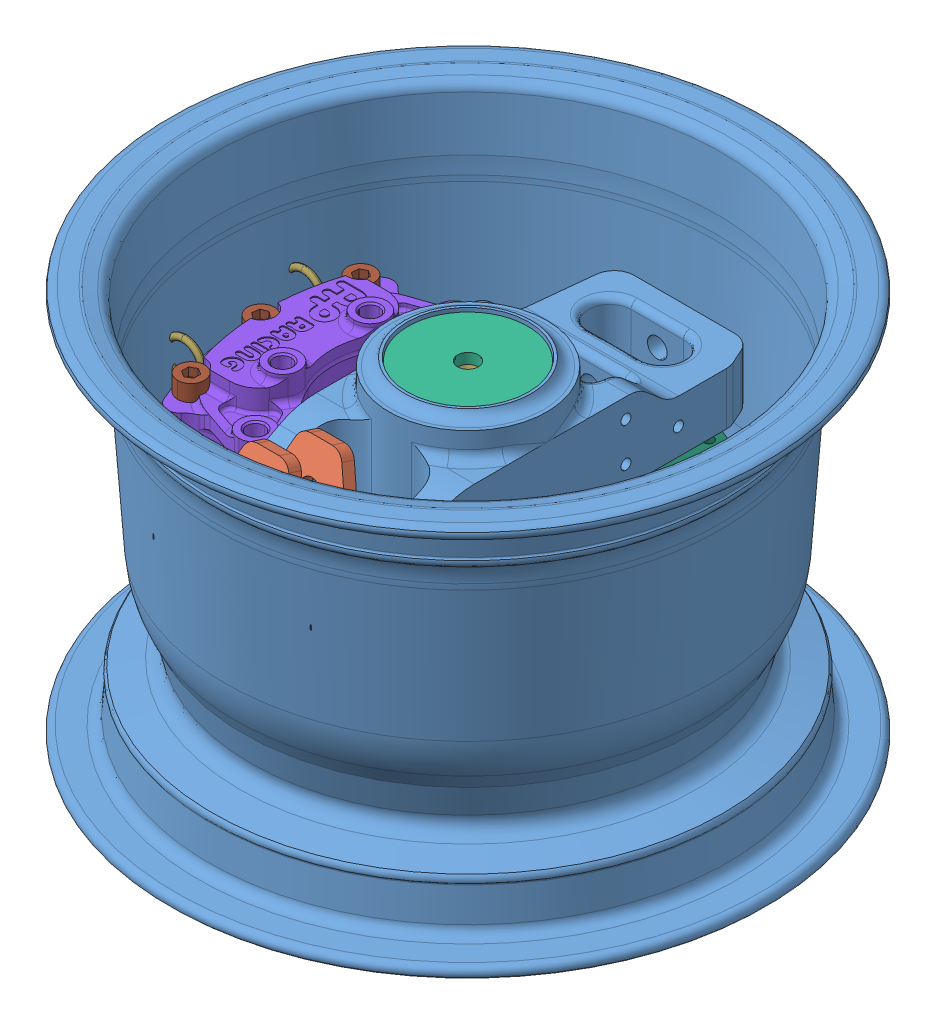
SolidWorks assembly WT-FRA0100-AH-Corner Assembly1, configuration Default. Lengths in mm.
Overall size (569.63 213.5 569.63).
47 component instances, 24 part files, 46 mates.
Components (placement in the parent):
- WT-FR####-AF-Upright1-1: WT-FR####-AF-Upright1 [Default] x (-1 0 0) z (0 0 -1) size (101.76 54.5 217.79)
- WT-FR####-AA-Camber Block1-1: WT-FR####-AA-Camber Block1 [Default] at (0 -9.355 94.5987) x (1 0 0) z (0 0.311078 0.950384) size (47.63 44.45 33.35)
- WT-FR10101-AB-Wheel Hub Front1-1: WT-FR10101-AB-Wheel Hub Front1 [Front] at (0 -47.0214 0) x (-0.796957 0 0.604036) z (0.604036 0 0.796957) size (96.32 138.68 96.32)
- FR1985-1932-TheTimkenCompany-3D-01-05-2023.stp1-1: FR1985-1932-TheTimkenCompany-3D-01-05-2023.stp1 [Default] at (0 -2.8702 0) x (0 -1 0) z (0.543016 0 0.839722) size (21.39 58.74 58.74)
- FR1985-1932-TheTimkenCompany-3D-01-05-2023.stp1-2: FR1985-1932-TheTimkenCompany-3D-01-05-2023.stp1 [Default] at (0 2.8702 0) x (0 1 0) z (-0.546944 0 0.837169) size (21.39 58.74 58.74)
- WT-FR####-AA-Front Grease Seal1-1: WT-FR####-AA-Front Grease Seal1 [Default] at (0 -24.9191 0) x (0.858041 0 -0.513581) z (0.513581 0 0.858041) size (58.42 7.71 58.42)
- WT-FR10106-AB-Backing Plate1-1: WT-FR10106-AB-Backing Plate1 [Default] at (0 21.8126 0) x (-0.663672 0 -0.748024) z (-0.748024 0 0.663672) size (57.91 5.08 57.91)
- WT-FR####-AB-Misuni Drive Pins1-1: WT-FR####-AB-Misuni Drive Pins1 [Default] at (31.8783 -46.4514 -24.1614) x (0 -1 0) z (0.99943 0 0.033765) size (21.1 11.95 11.95)
- WT-FR####-AB-Misuni Drive Pins1-2: WT-FR####-AB-Misuni Drive Pins1 [Default] at (-24.1614 -46.4514 -31.8783) x (0 -1 0) z (0.033765 0 -0.99943) size (21.1 11.95 11.95)
- WT-FR####-AB-Misuni Drive Pins1-3: WT-FR####-AB-Misuni Drive Pins1 [Default] at (-31.8783 -46.4514 24.1614) x (0 -1 0) z (-0.99943 0 -0.033765) size (21.1 11.95 11.95)
- WT-FR####-AB-Misuni Drive Pins1-4: WT-FR####-AB-Misuni Drive Pins1 [Default] at (24.1614 -46.4514 31.8783) x (0 -1 0) z (-0.033765 0 0.99943) size (21.1 11.95 11.95)
- FR-CP4227-2S01-1: FR-CP4227-2S01 [Default] at (15.8532 -32.3212 -0.8308) x (1 0 0) z (0 0 -1) size (71.54 66.42 130.94)
  - CP4227-2S0.STEP-1: CP4227-2S0.STEP [Default] x (0 0 -1) z (0 -1 0) size (130.94 71.54 66.42)
    - CP4227-101.STEP-1: CP4227-101.STEP [Default] at origin size (112 60.5 34.68)
    - CP4227-102.STEP-1: CP4227-102.STEP [Default] x (-1 0 0) z (0 0 -1) size (109 47.57 30.98)
    - cp3049-40a_CP4226-103.STEP-1: cp3049-40a_CP4226-103.STEP [Default] at (-23.4668 -94.12 -10.305) size (25.2 25.2 14.87)
    - cp3049-40a_CP4226-103.STEP-2: cp3049-40a_CP4226-103.STEP [Default] at (-23.4668 -94.12 10.305) x (-0.98369 0.179874 0) z (0 0 -1) size (25.2 25.2 14.87)
    - cp3049-40a_CP4226-103.STEP-3: cp3049-40a_CP4226-103.STEP [Default] at (23.4668 -94.12 10.305) x (-0.960147 0.279495 0) z (0 0 -1) size (25.2 25.2 14.87)
    - cp3049-40a_CP4226-103.STEP-4: cp3049-40a_CP4226-103.STEP [Default] at (23.4668 -94.12 -10.305) size (25.2 25.2 14.87)
    - cp3838-M08x1.25m_CP4477-110.STEP-1: cp3838-M08x1.25m_CP4477-110.STEP [Default] at (-41.1 -109.6 19.55) x (-0.998897 0.046962 0) z (0 0 -1) size (13 13 46)
    - cp3838-M08x1.25m_CP4477-110.STEP-2: cp3838-M08x1.25m_CP4477-110.STEP [Default] at (0 -116.83 19.55) x (-0.99038 0.138378 0) z (0 0 -1) size (13 13 46)
    - cp3838-M08x1.25m_CP4477-110.STEP-3: cp3838-M08x1.25m_CP4477-110.STEP [Default] at (41.1 -109.6 19.55) x (-1 -0.000032 0) z (0 0 -1) size (13 13 46)
    - cp4226-104_CP4226-104.STEP-1: cp4226-104_CP4226-104.STEP [Default] at (-29.0318 -116.44 -31.75) x (0 0 1) z (1 0 0) size (61.35 20.1 3)
    - cp4226-104_CP4226-104.STEP-2: cp4226-104_CP4226-104.STEP [Default] at (29.0318 -116.44 -31.75) x (0 0 1) z (1 0 0) size (61.35 20.1 3)
    - CP4469-101.STEP-1: CP4469-101.STEP [Default] at (-65.47 -82.62 -23.98) x (0 0.474307 -0.88036) z (1 0 0) size (9.24 8.21 29.15)
    - CP4469-101.STEP-2: CP4469-101.STEP [Default] at (65.47 -82.62 -23.98) x (0 0.509894 0.860237) z (-1 0 0) size (9.24 8.21 29.15)
    - CP4226-4m.STEP-1: CP4226-4m.STEP [Default] at (10.0433 -40.2815 10.305) x (0.970296 0.241922 0) z (0 0 -1) size (39.7 43.64 7)
    - CP4226-4m.STEP-2: CP4226-4m.STEP [Default] at (10.0433 -40.2815 -10.305) x (-0.970296 -0.241922 0) z (0 0 1) size (39.7 43.64 7)
    - CP4226-4m.STEP-3: CP4226-4m.STEP [Default] at (-10.0433 -40.2815 -10.305) x (-0.970296 0.241922 0) z (0 0 1) size (39.7 43.64 7)
    - CP4226-4m.STEP-4: CP4226-4m.STEP [Default] at (-10.0433 -40.2815 10.305) x (0.970296 -0.241922 0) z (0 0 -1) size (39.7 43.64 7)
- BR-FR20601-AA-Brake Rotor1-1: BR-FR20601-AA-Brake Rotor1 [Default] at (0 -32.3212 0) x (-0.921589 0 -0.388168) z (0.388168 0 -0.921589) size (190.5 4.76 190.5)
- BR-FR20602-AC-Brake Hat1-2: BR-FR20602-AC-Brake Hat1 [Default] at (0 -32.3212 0) x (-0.796957 0 0.604036) z (-0.604036 0 -0.796957) size (120.29 4.76 113.7)
- BR-FR20603-AA-Floating Bobbins1-1: BR-FR20603-AA-Floating Bobbins1 [Default] at (-7.5184 -32.4958 -59.8547) x (0.90465 0 -0.426156) z (-0.426156 0 -0.90465) size (12.7 8.29 12.7)
- BR-FR20603-AA-Floating Bobbins1-2: BR-FR20603-AA-Floating Bobbins1 [Default] at (48.0765 -32.4958 -36.4384) x (0.821387 0 0.570372) z (0.570372 0 -0.821387) size (12.7 8.29 12.7)
- BR-FR20603-AA-Floating Bobbins1-3: BR-FR20603-AA-Floating Bobbins1 [Default] at (55.5948 -32.4958 23.4162) x (-0.083263 0 0.996528) z (0.996528 0 0.083263) size (12.7 8.29 12.7)
- BR-FR20603-AA-Floating Bobbins1-4: BR-FR20603-AA-Floating Bobbins1 [Default] at (7.5184 -32.4958 59.8547) x (-0.90465 0 0.426156) z (0.426156 0 0.90465) size (12.7 8.29 12.7)
- BR-FR20603-AA-Floating Bobbins1-5: BR-FR20603-AA-Floating Bobbins1 [Default] at (-48.0765 -32.4958 36.4384) x (-0.821387 0 -0.570372) z (-0.570372 0 0.821387) size (12.7 8.29 12.7)
- BR-FR20603-AA-Floating Bobbins1-6: BR-FR20603-AA-Floating Bobbins1 [Default] at (-55.5948 -32.4958 -23.4162) x (0.083263 0 -0.996528) z (-0.996528 0 -0.083263) size (12.7 8.29 12.7)
- WT-FR20104-AC-Sensor Ring1-1: WT-FR20104-AC-Sensor Ring1 [Default] at (0 -28.3524 0) x (-0.796957 0 0.604036) z (0 -1 0) size (113.66 114.3 1.59)
- WT-FR00201-AA-OZ Centerlock 10in Wheel1-1: WT-FR00201-AA-OZ Centerlock 10in Wheel1 [Default] at (0 -58.4514 0) x (-0.388168 0 0.921589) z (0 -1 0) size (288.79 288.79 189.86)
- WT-FR10102-AA-Centerlock Nut1-1: WT-FR10102-AA-Centerlock Nut1 [Default] at (0 -109.0714 0) x (-0.796957 0 0.604036) z (0.604036 0 0.796957) size (66 31.75 66)
- WT_FRA####-AA-Toe Bracket1-1: WT_FRA####-AA-Toe Bracket1 [Default] at (15.6652 35.2295 -63.5947) x (1 0 0) z (0 0 -1) (suppressed, hidden)
- WT-FR00202-AA-Hoosier R25B 16x7_5-101-1: WT-FR00202-AA-Hoosier R25B 16x7_5-101 [Default] at (0 -36.4514 0) x (0.836753 0 -0.547581) z (0 1 0) size (411.48 411.48 213.5)
- WT-A0100-AB-Toe Bracket1-1: WT-A0100-AB-Toe Bracket1 [Default] at (15.6652 -39.4306 -3.128) size (40.8 50.39 55.24)
  - WT-FB-Toe Base Plate11-1: WT-FB-Toe Base Plate11 [Default] at (22.5935 33.4208 -28.102) size (3.17 37.93 55.25)
  - WT-FB-Toe Bottom Clevis11-1: WT-FB-Toe Bottom Clevis11 [Default] at (-402.1509 25.2365 -16.926) x (1 0 0) z (0 0 -1) size (40.8 37.86 3.17)
  - WT-GA-Toe Top Clevis11-1: WT-GA-Toe Top Clevis11 [Default] at (102.0031 -4.5841 -39.278) x (1 0 0) z (0 0 -1) size (40.6 42.28 3.17)
Mates (geometry in assembly coordinates):
- Concentric1: concentric: cylinder of WT-FR####-AF-Upright-1 through (0 -55.5512 0) axis (0 -1 0) radius 29.3687
- Coincident3: coincident anti-aligned: plane of WT-FR####-AF-Upright-1 through (0 0 0) normal (0 0 -1)
- Coincident4: coincident anti-aligned: plane of WT-FR####-AF-Upright-1 through (0 0 0) normal (-1 0 0)
- Coincident5: coincident aligned: plane of WT-FR####-AF-Upright-1 through (0 0 0) normal (0 1 0)
- Coincident6: coincident anti-aligned: plane of WT-FR####-AF-Upright-1 through (119.0541 -3.3374 112.9831) normal (0 0.950384 -0.311078); plane of WT-FR####-AA-Camber Block-1 through (0 -9.355 94.5987) normal (0 -0.950384 0.311078)
- Concentric2: concentric aligned: cylinder of WT-FR####-AF-Upright-1 through (-12.7 -9.355 94.5987) axis (0 0.950384 -0.311078) radius 4; cylinder of WT-FR####-AA-Camber Block-1 through (-12.7 -0.3026 91.6357) axis (0 0.950384 -0.311078) radius 4.5
- Concentric3: concentric aligned: cylinder of WT-FR####-AF-Upright-1 through (12.7 -9.355 94.5987) axis (0 0.950384 -0.311078) radius 4; cylinder of WT-FR####-AA-Camber Block-1 through (12.7 -0.3026 91.6357) axis (0 0.950384 -0.311078) radius 4.5
- Concentric4: concentric anti-aligned: cylinder of WT-FR####-AF-Upright-1 through (0 -55.5512 0) axis (0 -1 0) radius 29.3687; cylinder of WT-FR10101-AB-Wheel Hub Front-1 through (0 -47.0214 0) axis (0 1 0) radius 14.2875
- Concentric5: concentric anti-aligned: cylinder of WT-FR####-AF-Upright-1 through (0 -55.5512 0) axis (0 -1 0) radius 29.3687; cylinder of FR1985-1932-TheTimkenCompany-3D-01-05-2023.stp-1 through (0 -11.0325 0) axis (0 1 0) radius 29.3687
- Coincident7: coincident anti-aligned: plane of WT-FR####-AF-Upright-1 through (0 -3.175 29.3687) normal (0 -1 0); plane of FR1985-1932-TheTimkenCompany-3D-01-05-2023.stp-1 through (13.9388 -3.175 21.555) normal (0 1 0)
- Concentric6: concentric aligned: cylinder of WT-FR####-AF-Upright-1 through (0 -55.5512 0) axis (0 -1 0) radius 29.3687; cylinder of FR1985-1932-TheTimkenCompany-3D-01-05-2023.stp-2 through (0 11.0325 0) axis (0 -1 0) radius 29.3687
- Coincident8: coincident anti-aligned: plane of WT-FR####-AF-Upright-1 through (0 3.175 29.3687) normal (0 1 0); plane of FR1985-1932-TheTimkenCompany-3D-01-05-2023.stp-2 through (-14.0396 3.175 21.4895) normal (0 -1 0)
- Concentric7: concentric anti-aligned: cylinder of WT-FR####-AF-Upright-1 through (0 -55.5512 0) axis (0 -1 0) radius 29.3687; cylinder of WT-FR####-AA-Front Grease Seal-1 through (0 -24.9191 0) axis (0 1 0) radius 29.21
- Coincident9: coincident anti-aligned: plane of FR1985-1932-TheTimkenCompany-3D-01-05-2023.stp-1 through (9.9468 -22.225 15.3817) normal (0 -1 0); plane of WT-FR####-AA-Front Grease Seal-1 through (15.0017 -22.225 25.0634) normal (0 1 0)
- Coincident10: coincident anti-aligned: plane of WT-FR10101-AB-Wheel Hub Front-1 through (15.1507 -29.9399 19.9897) normal (0 1 0); plane of WT-FR####-AA-Front Grease Seal-1 through (7.3378 -29.9399 12.2593) normal (0 -1 0)
- Concentric8: concentric anti-aligned: cylinder of WT-FR####-AF-Upright-1 through (0 -55.5512 0) axis (0 -1 0) radius 29.3687; cylinder of WT-FR10106-AB-Backing Plate-1 through (0 21.8126 0) axis (0 1 0) radius 5.0419
- Coincident11: coincident anti-aligned: plane of WT-FR10101-AB-Wheel Hub Front-1 through (0 21.8126 0) normal (0 1 0); plane of WT-FR10106-AB-Backing Plate-1 through (-21.6598 21.8126 19.2173) normal (0 -1 0)
- Concentric9: concentric anti-aligned: cylinder of WT-FR10101-AB-Wheel Hub Front-1 through (31.8783 -47.0214 -24.1614) axis (0 1 0) radius 3.4; cylinder of WT-FR####-AB-Misuni Drive Pins-1 through (31.8783 -46.4514 -24.1614) axis (0 -1 0) radius 4
- Coincident12: coincident anti-aligned: plane of WT-FR10101-AB-Wheel Hub Front-1 through (31.7119 -58.4514 41.8403) normal (0 -1 0); plane of WT-FR####-AB-Misuni Drive Pins-1 through (32.08 -58.4514 -30.133) normal (0 1 0)
- Coincident13: coincident anti-aligned: plane of WT-FR####-AF-Upright-1 through (0 -15.8212 0) normal (0 1 0); plane of FR-CP4227-2S0-1/CP4227-2S0.STEP-1/CP4227-101.STEP-1 through (-91.7668 -15.8212 -27.6635) normal (0 -1 0)
- Concentric10: concentric anti-aligned: cylinder of WT-FR####-AF-Upright-1 through (-55.6468 -25.9812 47.1692) axis (0 -1 0) radius 4.2; cylinder of FR-CP4227-2S0-1/CP4227-2S0.STEP-1/CP4227-101.STEP-1 through (-55.6468 -32.3374 47.1692) axis (0 1 0) radius 4.25
- Concentric11: concentric anti-aligned: cylinder of WT-FR####-AF-Upright-1 through (-55.6468 -25.9812 -48.8308) axis (0 -1 0) radius 4.2; cylinder of FR-CP4227-2S0-1/CP4227-2S0.STEP-1/CP4227-101.STEP-1 through (-55.6468 -32.3374 -48.8308) axis (0 1 0) radius 4.25
- Symmetric1: symmetric aligned: plane of FR-CP4227-2S0-1/CP4227-2S0.STEP-1 through (15.8532 -32.3212 -0.8308) normal (0 1 0); plane of BR-FR20601-AA-Brake Rotor-1 through (0 -34.7024 0) normal (0 -1 0); plane of BR-FR20601-AA-Brake Rotor-1 through (0 -29.9399 0) normal (0 1 0)
- Concentric12: concentric anti-aligned: cylinder of WT-FR10101-AB-Wheel Hub Front-1 through (0 -47.0214 0) axis (0 1 0) radius 27.4096; cylinder of BR-FR20601-AA-Brake Rotor-1 through (0 -29.9399 0) axis (0 -1 0) radius 95.25
- Concentric13: concentric anti-aligned: cylinder of BR-FR20601-AA-Brake Rotor-1 through (-7.5184 -29.9399 -59.8547) axis (0 -1 0) radius 5.5563; cylinder of BR-FR20603-AA-Floating Bobbins-1 through (-7.5184 -32.4958 -59.8547) axis (0 1 0) radius 5.3721
- Coincident14: coincident anti-aligned: plane of BR-FR20601-AA-Brake Rotor-1 through (0 -29.9399 0) normal (0 1 0); plane of BR-FR20603-AA-Floating Bobbins-1 through (-10.2245 -29.9399 -65.5992) normal (0 -1 0)
- Coincident15: coincident aligned: plane of BR-FR20601-AA-Brake Rotor-1 through (0 -29.9399 0) normal (0 1 0); plane of BR-FR20602-AC-Brake Hat-2 through (48.0765 -29.9399 -36.4384) normal (0 1 0)
- Parallel1: parallel anti-aligned: plane of WT-FR10101-AB-Wheel Hub Front-1 through (16.9464 -34.7024 -12.8441) normal (0.388168 0 -0.921589); plane of BR-FR20602-AC-Brake Hat-2 through (16.923 -34.7024 -12.8264) normal (-0.388168 0 0.921589)
- Concentric15: concentric anti-aligned: cylinder of BR-FR20602-AC-Brake Hat-2 through (-7.5184 -29.9399 -59.8547) axis (0 -1 0) radius 5.5563; cylinder of BR-FR20603-AA-Floating Bobbins-1 through (-7.5184 -32.4958 -59.8547) axis (0 1 0) radius 5.3721
- Concentric16: concentric anti-aligned: cylinder of BR-FR20602-AC-Brake Hat-2 through (-55.5948 -29.9399 -23.4162) axis (0 -1 0) radius 5.5563; cylinder of BR-FR20603-AA-Floating Bobbins-6 through (-55.5948 -32.4958 -23.4162) axis (0 1 0) radius 5.3721
- Concentric17: concentric anti-aligned: cylinder of BR-FR20601-AA-Brake Rotor-1 through (0 -29.9399 0) axis (0 -1 0) radius 95.25; cylinder of WT-FR20104-AC-Sensor Ring-1 through (0 -29.9399 0) axis (0 1 0) radius 57.15
- Coincident17: coincident anti-aligned: plane of BR-FR20601-AA-Brake Rotor-1 through (0 -29.9399 0) normal (0 1 0); plane of WT-FR20104-AC-Sensor Ring-1 through (0 -29.9399 0) normal (0 -1 0)
- Concentric18: concentric anti-aligned: cylinder of BR-FR20602-AC-Brake Hat-2 through (-33.4005 -34.7024 25.3151) axis (0 1 0) radius 1.27; cylinder of WT-FR20104-AC-Sensor Ring-1 through (-33.4005 -28.3524 25.3151) axis (0 -1 0) radius 1.27
- Concentric19: concentric anti-aligned: cylinder of WT-FR10101-AB-Wheel Hub Front-1 through (0 -47.0214 0) axis (0 1 0) radius 23.6195; cylinder of WT-FR00201-AA-OZ Centerlock 10in Wheel-1 through (0 -58.4514 0) axis (0 -1 0) radius 27.5
- Concentric20: concentric anti-aligned: cylinder of WT-FR####-AB-Misuni Drive Pins-2 through (-24.1614 -46.4514 -31.8783) axis (0 -1 0) radius 5.975; cylinder of WT-FR00201-AA-OZ Centerlock 10in Wheel-1 through (-24.1614 -58.4514 -31.8783) axis (0 1 0) radius 6
- Coincident18: coincident anti-aligned: plane of WT-FR10101-AB-Wheel Hub Front-1 through (31.7119 -58.4514 41.8403) normal (0 -1 0); plane of WT-FR00201-AA-OZ Centerlock 10in Wheel-1 through (-26.2653 -58.4514 -11.0628) normal (0 1 0)
- Concentric22: concentric aligned: cone of WT-FR00201-AA-OZ Centerlock 10in Wheel-1 through (0 -83.4514 0) axis (0 1 0); cone of WT-FR10102-AA-Centerlock Nut-1 through (0 -84.452 0) axis (0 1 0)
- Concentric23: concentric anti-aligned: cylinder of WT-FR10101-AB-Wheel Hub Front-1 through (-29.0919 -106.0714 -38.3835) axis (0.604036 0 0.796957) radius 2; cylinder of WT-FR10102-AA-Centerlock Nut-1 through (19.9332 -106.0714 26.2996) axis (-0.604036 0 -0.796957) radius 1.9844
- Coincident19: coincident anti-aligned: plane of WT-FR####-AF-Upright-1 through (38.2587 113.2225 0) normal (1 0 0); plane of WT_FRA####-AA-Toe Bracket-1/WT-FB-Toe Base Plate1-1 through (38.2587 9.8253 -11.6772) normal (-1 0 0)
- Concentric26: concentric anti-aligned: cylinder of WT-FR####-AF-Upright-1 through (38.2587 2.4262 -38.1635) axis (1 0 0) radius 2.4574; cylinder of WT_FRA####-AA-Toe Bracket-1/WT-FB-Toe Base Plate1-1 through (38.2587 2.4262 -38.1635) axis (-1 0 0) radius 2.4574
- Concentric27: concentric anti-aligned: cylinder of WT-FR####-AF-Upright-1 through (38.2587 -13.2812 -63.5635) axis (1 0 0) radius 2.4574; cylinder of WT_FRA####-AA-Toe Bracket-1/WT-FB-Toe Base Plate1-1 through (38.2587 -13.2812 -63.5635) axis (-1 0 0) radius 2.4574
- Concentric28: concentric anti-aligned: cylinder of WT-FR10101-AB-Wheel Hub Front-1 through (0 -47.0214 0) axis (0 1 0) radius 23.6195; cylinder of WT-FR00202-AA-Hoosier R25B 16x7_5-10-1 through (0 -36.4514 0) axis (0 -1 0) radius 205.74
- Coincident20: coincident anti-aligned: plane of WT-FR00201-AA-OZ Centerlock 10in Wheel-1 through (-130.2184 52.4486 -54.8472) normal (0 -1 0); plane of WT-FR00202-AA-Hoosier R25B 16x7_5-10-1 through (-69.5428 52.4486 -106.2676) normal (0 1 0)
- Distance1: distance = 1.9582 mm aligned: plane of WT_FRA####-AA-Toe Bracket-1/WT-FB-Toe Base Plate1-1 through (41.4337 9.993 -58.8028) normal (0 1 0); plane of WT-FR####-AF-Upright-1 through (0 11.9512 30.6387) normal (0 1 0)
- Coincident21: coincident anti-aligned: plane of WT-FR####-AF-Upright1-1 through (38.2587 113.2225 0) normal (1 0 0); plane of WT-A0100-AB-Toe Bracket1-1/WT-FB-Toe Base Plate11-1 through (38.2587 -14.0265 -7.4146) normal (-1 0 0)
- Parallel3: parallel aligned: plane of WT-FR####-AF-Upright1-1 through (0 11.9512 30.6387) normal (0 1 0); plane of WT-A0100-AB-Toe Bracket1-1/WT-FB-Toe Base Plate11-1 through (41.4337 11.2059 0.7048) normal (0 1 0)
